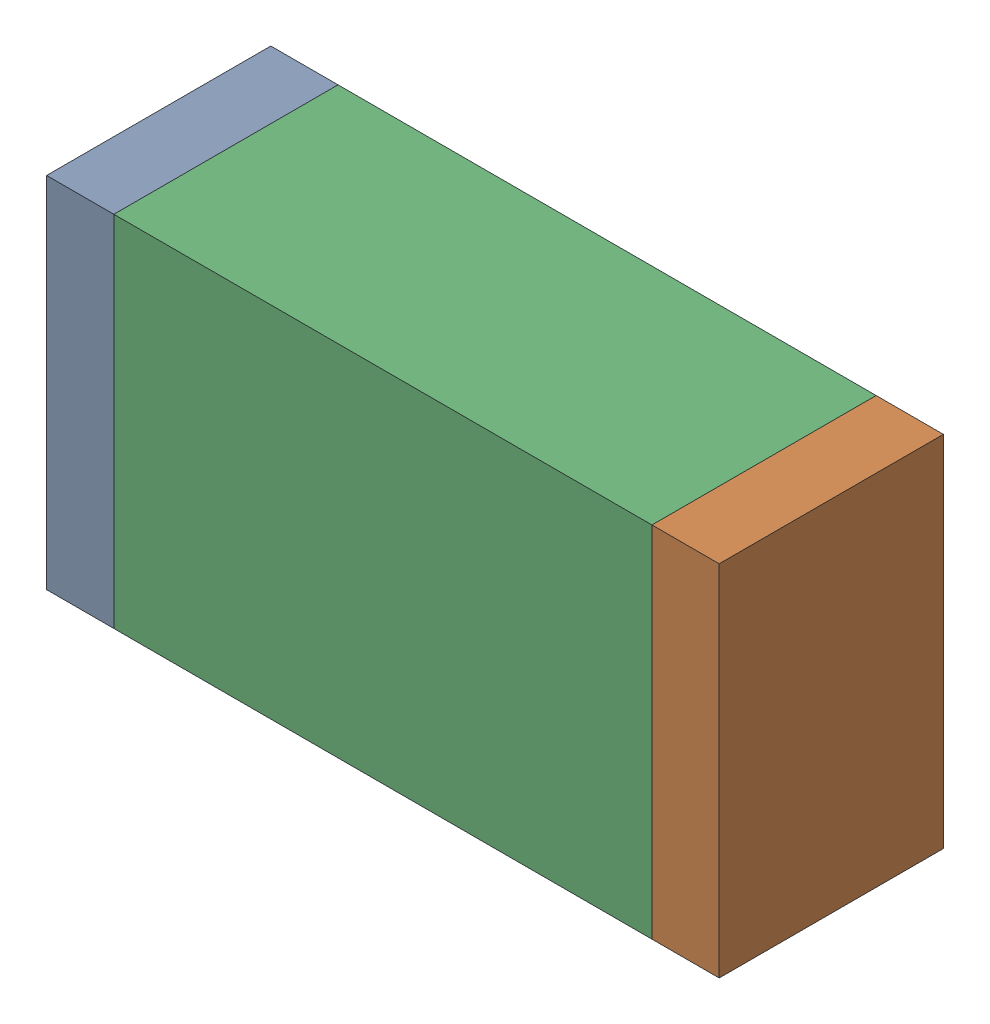
SolidWorks assembly R39, configuration Default. Lengths in mm.
Overall size (1.5 0.8 0.5).
6 component instances, 2 part files, 0 mates.
Components (placement in the parent):
- 836752496-1: 836752496 [Default] at (130.225 51.2 0) size (0.15 0.8 0.5)
  - Extruded_2-1: Extruded_2 [Default] at origin size (0.15 0.8 0.5)
- 836752496-2: 836752496 [Default] at (131.575 51.2 0) size (0.15 0.8 0.5)
  - Extruded_2-1: Extruded_2 [Default] at origin size (0.15 0.8 0.5)
- 836752368-1: 836752368 [Default] at (130.9 51.2 0) size (1.2 0.8 0.5)
  - Extruded-1: Extruded [Default] at origin size (1.2 0.8 0.5)
